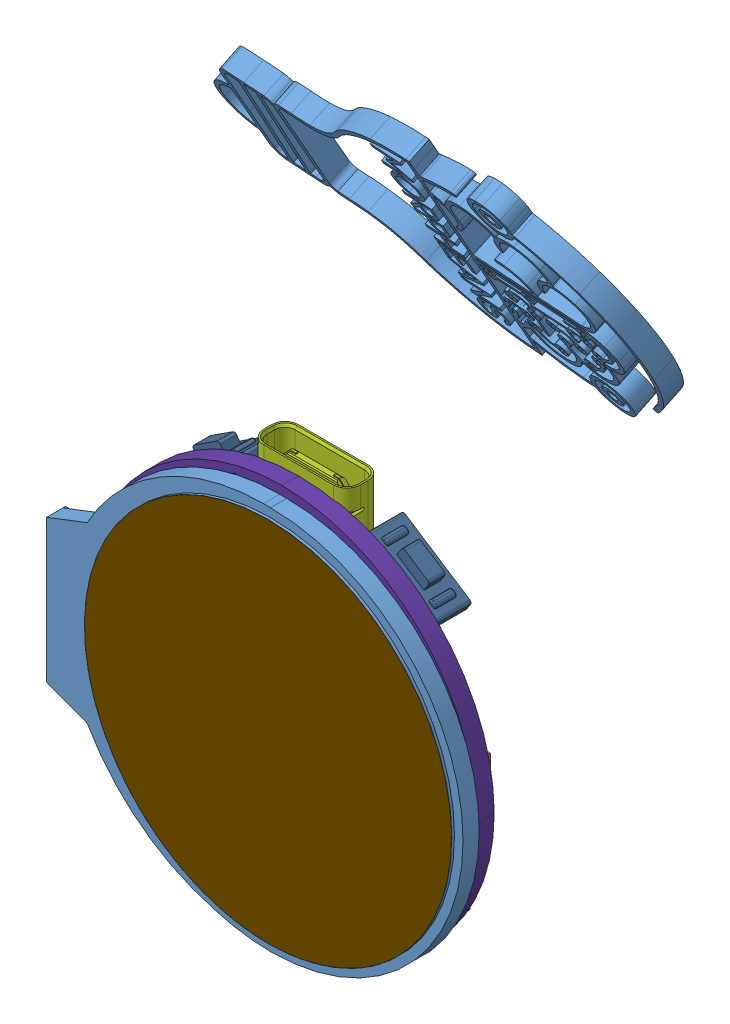
SolidWorks assembly upitchuS2round, configuration Défaut. Lengths in mm.
Overall size (45.27 66.43 21.26).
144 component instances, 19 part files, 2 mates.
Components (placement in the parent):
- upitchuS2round.step-1: upitchuS2round.step [Défaut] at origin size (38.56 37.01 7.25)
  - LH128R.step-1: LH128R.step [Défaut] at (71.778 -101.727 1.95) x (0 -1 0) z (0 0 1) size (35.61 38.56 2.01)
    - SOLID.step-1: SOLID.step [Défaut] at origin size (35.61 38.56 2.01)
  - 2450AT18A100E--3DModel-STEP-56544.step-1: 2450AT18A100E--3DModel-STEP-56544.step [Défaut] at (91.65 -99.4 -0.05) x (0 1 0) z (0 0 -1) size (3.2 1.4 1.6)
    - COMPOUND.step-1: COMPOUND.step [Défaut] at origin size (3.2 1.4 1.6)
  - C_0402_1005Metric.step-1: C_0402_1005Metric.step [Défaut] at (61 -93.88 -0.05) x (0 -1 0) z (0 0 -1) size (1 0.5 0.5)
    - SOLID-0.step-1: SOLID-0.step [Défaut] at origin size (1 0.5 0.5)
  - C_0402_1005Metric.step-2: C_0402_1005Metric.step [Défaut] at (83.5 -95.08 -0.05) x (0 -1 0) z (0 0 -1) size (1 0.5 0.5)
    - SOLID-0.step-1: SOLID-0.step [Défaut] at origin size (1 0.5 0.5)
  - C_0402_1005Metric.step-3: C_0402_1005Metric.step [Défaut] at (77.72 -113.2 -0.05) x (-1 0 0) z (0 0 -1) size (1 0.5 0.5)
    - SOLID-0.step-1: SOLID-0.step [Défaut] at origin size (1 0.5 0.5)
  - C_0402_1005Metric.step-4: C_0402_1005Metric.step [Défaut] at (89 -94.98 -0.05) x (0 1 0) z (0 0 -1) size (1 0.5 0.5)
    - SOLID-0.step-1: SOLID-0.step [Défaut] at origin size (1 0.5 0.5)
  - C_0402_1005Metric.step-5: C_0402_1005Metric.step [Défaut] at (88.4 -97.02 -0.05) x (0 -1 0) z (0 0 -1) size (1 0.5 0.5)
    - SOLID-0.step-1: SOLID-0.step [Défaut] at origin size (1 0.5 0.5)
  - C_0402_1005Metric.step-6: C_0402_1005Metric.step [Défaut] at (68.28 -96.5 -0.05) x (1 0 0) z (0 0 -1) size (1 0.5 0.5)
    - SOLID-0.step-1: SOLID-0.step [Défaut] at origin size (1 0.5 0.5)
  - C_0402_1005Metric.step-7: C_0402_1005Metric.step [Défaut] at (83.5 -97.08 -0.05) x (0 1 0) z (0 0 -1) size (1 0.5 0.5)
    - SOLID-0.step-1: SOLID-0.step [Défaut] at origin size (1 0.5 0.5)
  - C_0402_1005Metric.step-8: C_0402_1005Metric.step [Défaut] at (70 -96.12 -0.05) x (0 -1 0) z (0 0 -1) size (1 0.5 0.5)
    - SOLID-0.step-1: SOLID-0.step [Défaut] at origin size (1 0.5 0.5)
  - C_0402_1005Metric.step-9: C_0402_1005Metric.step [Défaut] at (70 -94.12 -0.05) x (0 1 0) z (0 0 -1) size (1 0.5 0.5)
    - SOLID-0.step-1: SOLID-0.step [Défaut] at origin size (1 0.5 0.5)
  - C_0402_1005Metric.step-10: C_0402_1005Metric.step [Défaut] at (90.4 -107.8 -0.05) x (0 -1 0) z (0 0 -1) size (1 0.5 0.5)
    - SOLID-0.step-1: SOLID-0.step [Défaut] at origin size (1 0.5 0.5)
  - C_0402_1005Metric.step-11: C_0402_1005Metric.step [Défaut] at (91.6 -107.8 -0.05) x (0 1 0) z (0 0 -1) size (1 0.5 0.5)
    - SOLID-0.step-1: SOLID-0.step [Défaut] at origin size (1 0.5 0.5)
  - C_0402_1005Metric.step-12: C_0402_1005Metric.step [Défaut] at (83.52 -98.6 -0.05) x (1 0 0) z (0 0 -1) size (1 0.5 0.5)
    - SOLID-0.step-1: SOLID-0.step [Défaut] at origin size (1 0.5 0.5)
  - C_0402_1005Metric.step-13: C_0402_1005Metric.step [Défaut] at (89 -99 -0.05) x (0 -1 0) z (0 0 -1) size (1 0.5 0.5)
    - SOLID-0.step-1: SOLID-0.step [Défaut] at origin size (1 0.5 0.5)
  - C_0402_1005Metric.step-14: C_0402_1005Metric.step [Défaut] at (87.72 -100.8 -0.05) x (1 0 0) z (0 0 -1) size (1 0.5 0.5)
    - SOLID-0.step-1: SOLID-0.step [Défaut] at origin size (1 0.5 0.5)
  - C_0402_1005Metric.step-15: C_0402_1005Metric.step [Défaut] at (87 -110.88 -0.05) x (0 1 0) z (0 0 -1) size (1 0.5 0.5)
    - SOLID-0.step-1: SOLID-0.step [Défaut] at origin size (1 0.5 0.5)
  - C_0402_1005Metric.step-16: C_0402_1005Metric.step [Défaut] at (77.4 -103.48 -0.05) x (0 1 0) z (0 0 -1) size (1 0.5 0.5)
    - SOLID-0.step-1: SOLID-0.step [Défaut] at origin size (1 0.5 0.5)
  - C_0402_1005Metric.step-17: C_0402_1005Metric.step [Défaut] at (78.2 -112 -0.05) x (-1 0 0) z (0 0 -1) size (1 0.5 0.5)
    - SOLID-0.step-1: SOLID-0.step [Défaut] at origin size (1 0.5 0.5)
  - C_0402_1005Metric.step-18: C_0402_1005Metric.step [Défaut] at (80.2 -112 -0.05) x (-1 0 0) z (0 0 -1) size (1 0.5 0.5)
    - SOLID-0.step-1: SOLID-0.step [Défaut] at origin size (1 0.5 0.5)
  - C_0402_1005Metric.step-19: C_0402_1005Metric.step [Défaut] at (75.8 -108.4 -0.05) x (-1 0 0) z (0 0 -1) size (1 0.5 0.5)
    - SOLID-0.step-1: SOLID-0.step [Défaut] at origin size (1 0.5 0.5)
  - LED_0603_1608Metric.step-1: LED_0603_1608Metric.step [Défaut] at (72.6125 -98 -0.05) x (1 0 0) z (0 0 -1) size (1.6 0.8 1.1)
    - SOLID-1.step-1: SOLID-1.step [Défaut] at origin size (1.6 0.8 1.1)
  - SOT-23.step-1: SOT-23.step [Défaut] at (63.4 -93.4 -0.05) x (-1 0 0) z (0 0 -1) size (2.5 3 1.2)
    - SOLID-2.step-1: SOLID-2.step [Défaut] at origin size (2.5 3 1.2)
  - D_SOD-123.step-1: D_SOD-123.step [Défaut] at (70.1 -112 -0.05) x (1 0 0) z (0 0 -1) size (3.8 1.6 1.25)
    - SOLID-3.step-1: SOLID-3.step [Défaut] at origin size (3.8 1.6 1.25)
  - USB Type C Port (SMD Type).step-1: USB Type C Port (SMD Type).step [Défaut] at (76.2 -89.95 -1.55) size (8.94 7.9 4.2)
    - COMPOUND-4.step-1: COMPOUND-4.step [Défaut] at origin size (8.94 7.9 4.2)
  - L_0402_1005Metric.step-1: L_0402_1005Metric.step [Défaut] at (79.885 -113.2 -0.05) x (1 0 0) z (0 0 -1) size (1 0.5 0.5)
    - SOLID-5.step-1: SOLID-5.step [Défaut] at origin size (1 0.5 0.5)
  - L_0402_1005Metric.step-2: L_0402_1005Metric.step [Défaut] at (90.35 -105.7 -0.05) x (0 1 0) z (0 0 -1) size (1 0.5 0.5)
    - SOLID-5.step-1: SOLID-5.step [Défaut] at origin size (1 0.5 0.5)
  - L_0402_1005Metric.step-3: L_0402_1005Metric.step [Défaut] at (86.5 -98.85 -0.05) x (0 -1 0) z (0 0 -1) size (1 0.5 0.5)
    - SOLID-5.step-1: SOLID-5.step [Défaut] at origin size (1 0.5 0.5)
  - SOT-23.step-2: SOT-23.step [Défaut] at (74.75 -111.5 -0.05) x (1 0 0) z (0 0 -1) size (2.5 3 1.2)
    - SOLID-2.step-1: SOLID-2.step [Défaut] at origin size (2.5 3 1.2)
  - SOT-23.step-3: SOT-23.step [Défaut] at (69.25 -99 -0.05) x (1 0 0) z (0 0 -1) size (2.5 3 1.2)
    - SOLID-2.step-1: SOLID-2.step [Défaut] at origin size (2.5 3 1.2)
  - R_0402_1005Metric.step-1: R_0402_1005Metric.step [Défaut] at (70.2 -91.51 -0.05) x (0 1 0) z (0 0 -1) size (1 0.5 0.35)
    - SOLID-6.step-1: SOLID-6.step [Défaut] at origin size (1 0.5 0.35)
  - R_0402_1005Metric.step-2: R_0402_1005Metric.step [Défaut] at (75.69 -98.8 -0.05) x (-1 0 0) z (0 0 -1) size (1 0.5 0.35)
    - SOLID-6.step-1: SOLID-6.step [Défaut] at origin size (1 0.5 0.35)
  - R_0402_1005Metric.step-3: R_0402_1005Metric.step [Défaut] at (85.25 -98.85 -0.05) x (0 1 0) z (0 0 -1) size (1 0.5 0.35)
    - SOLID-6.step-1: SOLID-6.step [Défaut] at origin size (1 0.5 0.35)
  - R_0402_1005Metric.step-4: R_0402_1005Metric.step [Défaut] at (76.25 -96.89 -0.05) x (0 -1 0) z (0 0 -1) size (1 0.5 0.35)
    - SOLID-6.step-1: SOLID-6.step [Défaut] at origin size (1 0.5 0.35)
  - R_0402_1005Metric.step-5: R_0402_1005Metric.step [Défaut] at (75 -96.89 -0.05) x (0 -1 0) z (0 0 -1) size (1 0.5 0.35)
    - SOLID-6.step-1: SOLID-6.step [Défaut] at origin size (1 0.5 0.35)
  - R_0402_1005Metric.step-6: R_0402_1005Metric.step [Défaut] at (84.8 -111.11 -0.05) x (0 -1 0) z (0 0 -1) size (1 0.5 0.35)
    - SOLID-6.step-1: SOLID-6.step [Défaut] at origin size (1 0.5 0.35)
  - R_0402_1005Metric.step-7: R_0402_1005Metric.step [Défaut] at (73.5 -108.35 -0.05) x (1 0 0) z (0 0 -1) size (1 0.5 0.35)
    - SOLID-6.step-1: SOLID-6.step [Défaut] at origin size (1 0.5 0.35)
  - R_0402_1005Metric.step-8: R_0402_1005Metric.step [Défaut] at (70.5 -102.01 -0.05) x (0 1 0) z (0 0 -1) size (1 0.5 0.35)
    - SOLID-6.step-1: SOLID-6.step [Défaut] at origin size (1 0.5 0.35)
  - R_0402_1005Metric.step-9: R_0402_1005Metric.step [Défaut] at (69.99 -89.75 -0.05) x (1 0 0) z (0 0 -1) size (1 0.5 0.35)
    - SOLID-6.step-1: SOLID-6.step [Défaut] at origin size (1 0.5 0.35)
  - R_0402_1005Metric.step-10: R_0402_1005Metric.step [Défaut] at (72.31 -99.6 -0.05) x (-1 0 0) z (0 0 -1) size (1 0.5 0.35)
    - SOLID-6.step-1: SOLID-6.step [Défaut] at origin size (1 0.5 0.35)
  - R_0402_1005Metric.step-11: R_0402_1005Metric.step [Défaut] at (82.5 -90.25 -0.05) x (-1 0 0) z (0 0 -1) size (1 0.5 0.35)
    - SOLID-6.step-1: SOLID-6.step [Défaut] at origin size (1 0.5 0.35)
  - R_0402_1005Metric.step-12: R_0402_1005Metric.step [Défaut] at (83.75 -91.75 -0.05) x (-1 0 0) z (0 0 -1) size (1 0.5 0.35)
    - SOLID-6.step-1: SOLID-6.step [Défaut] at origin size (1 0.5 0.35)
  - R_0402_1005Metric.step-13: R_0402_1005Metric.step [Défaut] at (74.09 -100.8 -0.05) x (1 0 0) z (0 0 -1) size (1 0.5 0.35)
    - SOLID-6.step-1: SOLID-6.step [Défaut] at origin size (1 0.5 0.35)
  - R_0402_1005Metric.step-14: R_0402_1005Metric.step [Défaut] at (68.51 -91.4 -0.05) x (-1 0 0) z (0 0 -1) size (1 0.5 0.35)
    - SOLID-6.step-1: SOLID-6.step [Défaut] at origin size (1 0.5 0.35)
  - R_0402_1005Metric.step-15: R_0402_1005Metric.step [Défaut] at (87.76 -92 -0.05) x (-1 0 0) z (0 0 -1) size (1 0.5 0.35)
    - SOLID-6.step-1: SOLID-6.step [Défaut] at origin size (1 0.5 0.35)
  - R_0402_1005Metric.step-16: R_0402_1005Metric.step [Défaut] at (82.51 -113.4 -0.05) x (1 0 0) z (0 0 -1) size (1 0.5 0.35)
    - SOLID-6.step-1: SOLID-6.step [Défaut] at origin size (1 0.5 0.35)
  - R_0402_1005Metric.step-17: R_0402_1005Metric.step [Défaut] at (82.5 -112.2 -0.05) x (1 0 0) z (0 0 -1) size (1 0.5 0.35)
    - SOLID-6.step-1: SOLID-6.step [Défaut] at origin size (1 0.5 0.35)
  - R_0402_1005Metric.step-18: R_0402_1005Metric.step [Défaut] at (63 -112 -0.05) x (-1 0 0) z (0 0 -1) size (1 0.5 0.35)
    - SOLID-6.step-1: SOLID-6.step [Défaut] at origin size (1 0.5 0.35)
  - R_0402_1005Metric.step-19: R_0402_1005Metric.step [Défaut] at (88.8 -109.6 -0.05) x (0 -1 0) z (0 0 -1) size (1 0.5 0.35)
    - SOLID-6.step-1: SOLID-6.step [Défaut] at origin size (1 0.5 0.35)
  - R_0402_1005Metric.step-20: R_0402_1005Metric.step [Défaut] at (89.89 -111.2 -0.05) x (1 0 0) z (0 0 -1) size (1 0.5 0.35)
    - SOLID-6.step-1: SOLID-6.step [Défaut] at origin size (1 0.5 0.35)
  - R_0402_1005Metric.step-21: R_0402_1005Metric.step [Défaut] at (71.25 -113.75 -0.05) x (1 0 0) z (0 0 -1) size (1 0.5 0.35)
    - SOLID-6.step-1: SOLID-6.step [Défaut] at origin size (1 0.5 0.35)
  - R_0402_1005Metric.step-22: R_0402_1005Metric.step [Défaut] at (90.4 -110 -0.05) x (-1 0 0) z (0 0 -1) size (1 0.5 0.35)
    - SOLID-6.step-1: SOLID-6.step [Défaut] at origin size (1 0.5 0.35)
  - R_0402_1005Metric.step-23: R_0402_1005Metric.step [Défaut] at (75 -93.5 -0.05) x (0 -1 0) z (0 0 -1) size (1 0.5 0.35)
    - SOLID-6.step-1: SOLID-6.step [Défaut] at origin size (1 0.5 0.35)
  - R_0402_1005Metric.step-24: R_0402_1005Metric.step [Défaut] at (76.25 -93.49 -0.05) x (0 -1 0) z (0 0 -1) size (1 0.5 0.35)
    - SOLID-6.step-1: SOLID-6.step [Défaut] at origin size (1 0.5 0.35)
  - 1TS002G-2300-3500-CT.step-1: 1TS002G-2300-3500-CT.step [Défaut] at (67.67 -88.17 -1.8) x (0.838671 0.544639 0) z (0 0 1) size (7.63 3.64 4.2)
    - SOLID-7.step-1: SOLID-7.step [Défaut] at origin size (7.63 3.64 4.2)
  - 1TS002G-2300-3500-CT.step-2: 1TS002G-2300-3500-CT.step [Défaut] at (84.8 -88.21 -1.8) x (0.838671 -0.544639 0) z (0 0 1) size (7.63 3.64 4.2)
    - SOLID-7.step-1: SOLID-7.step [Défaut] at origin size (7.63 3.64 4.2)
  - 1TS002G-2300-3500-CT.step-3: 1TS002G-2300-3500-CT.step [Défaut] at (67.62 -115.03 -1.8) x (-0.838671 0.544639 0) z (0 0 1) size (7.63 3.64 4.2)
    - SOLID-7.step-1: SOLID-7.step [Défaut] at origin size (7.63 3.64 4.2)
  - 1TS002G-2300-3500-CT.step-4: 1TS002G-2300-3500-CT.step [Défaut] at (84.73 -115.03 -1.8) x (-0.838671 -0.544639 0) z (0 0 1) size (7.63 3.64 4.2)
    - SOLID-7.step-1: SOLID-7.step [Défaut] at origin size (7.63 3.64 4.2)
  - SKRPABE010.step-1: SKRPABE010.step [Défaut] at (78.25 -116.45 -0.05) x (0 1 0) z (-1 0 0) size (4.6 2.5 3.2)
    - SOLID-8.step-1: SOLID-8.step [Défaut] at origin size (4.6 2.5 3.2)
  - SKRPABE010.step-2: SKRPABE010.step [Défaut] at (74.05 -116.45 -0.05) x (0 1 0) z (-1 0 0) size (4.6 2.5 3.2)
    - SOLID-8.step-1: SOLID-8.step [Défaut] at origin size (4.6 2.5 3.2)
  - SOT-23-5.step-1: SOT-23-5.step [Défaut] at (67.4 -93.75 -0.05) x (0 1 0) z (0 0 -1) size (2.8 2.9 1.55)
    - SOLID-9.step-1: SOLID-9.step [Défaut] at origin size (2.8 2.9 1.55)
  - SOT-23-5.step-2: SOT-23-5.step [Défaut] at (72.5 -94.5 -0.05) x (0 1 0) z (0 0 -1) size (2.8 2.9 1.55)
    - SOLID-9.step-1: SOLID-9.step [Défaut] at origin size (2.8 2.9 1.55)
  - ESP32-S2.step-1: ESP32-S2.step [Défaut] at (82.9 -105.4 -0.05) x (-1 0 0) z (0 -1 0) size (7 0.9 7)
    - COMPOUND-10.step-1: COMPOUND-10.step [Défaut] at origin size (7 0.9 7)
  - ADXL345.step-1: ADXL345.step [Défaut] at (75.75 -107.35 -0.05) x (-1 0 0) z (0 0 -1) size (3 5 1)
    - SOLID-11.step-1: SOLID-11.step [Défaut] at origin size (3 5 1)
  - SOIC-8_3.9x4.9mm_P1.27mm.step-1: SOIC-8_3.9x4.9mm_P1.27mm.step [Défaut] at (79.75 -96.25 -0.05) x (0 -1 0) z (0 0 -1) size (6 4.9 1.75)
    - SOLID-12.step-1: SOLID-12.step [Défaut] at origin size (6 4.9 1.75)
  - ECS-400-10-36B-CKY-TR.step-1: ECS-400-10-36B-CKY-TR.step [Défaut] at (85.85 -95.95 -0.05) x (0 -1 0) z (1 0 0) size (2.5 0.65 2)
    - COMPOUND-13.step-1: COMPOUND-13.step [Défaut] at origin size (2.5 0.65 2)
  - R_0402_1005Metric.step-25: R_0402_1005Metric.step [Défaut] at (68.5 -101.25 -0.05) x (1 0 0) z (0 0 -1) size (1 0.5 0.35)
    - SOLID-6.step-1: SOLID-6.step [Défaut] at origin size (1 0.5 0.35)
  - R_0402_1005Metric.step-26: R_0402_1005Metric.step [Défaut] at (69.25 -105 -0.05) x (1 0 0) z (0 0 -1) size (1 0.5 0.35)
    - SOLID-6.step-1: SOLID-6.step [Défaut] at origin size (1 0.5 0.35)
  - R_0402_1005Metric.step-27: R_0402_1005Metric.step [Défaut] at (69.25 -106.75 -0.05) x (1 0 0) z (0 0 -1) size (1 0.5 0.35)
    - SOLID-6.step-1: SOLID-6.step [Défaut] at origin size (1 0.5 0.35)
  - C_0402_1005Metric.step-20: C_0402_1005Metric.step [Défaut] at (68.5 -102.75 -0.05) x (1 0 0) z (0 0 -1) size (1 0.5 0.5)
    - SOLID-0.step-1: SOLID-0.step [Défaut] at origin size (1 0.5 0.5)
  - COMPOUND-14.step-1: COMPOUND-14.step [Défaut] at origin size (36.13 36.13 1.6)
- cadran-3: cadran [Défaut] at (77.0293 -101.8029 3.7) x (0 -1 0) z (0 0 1) size (34 34 0.01)
- logomorpheans-1: logomorpheans [Défaut] at (57.1974 -44.8141 0.0133) x (0.010811 -0.87166 -0.489991) z (-0.049148 -0.489891 0.870397) size (26.41 42.02 2)
Mates (geometry in assembly coordinates):
- Coïncidente1: coincident anti-aligned: plane of upitchuS2round.step-1/LH128R.step-1/SOLID.step-1 through (77.0293 -101.8029 3.7) normal (0 0 1); plane of cadran-3 through (77.0293 -101.8029 3.7) normal (0 0 -1)
- Coaxiale1: concentric aligned: circle of upitchuS2round.step-1/LH128R.step-1/SOLID.step-1; circle of cadran-3
